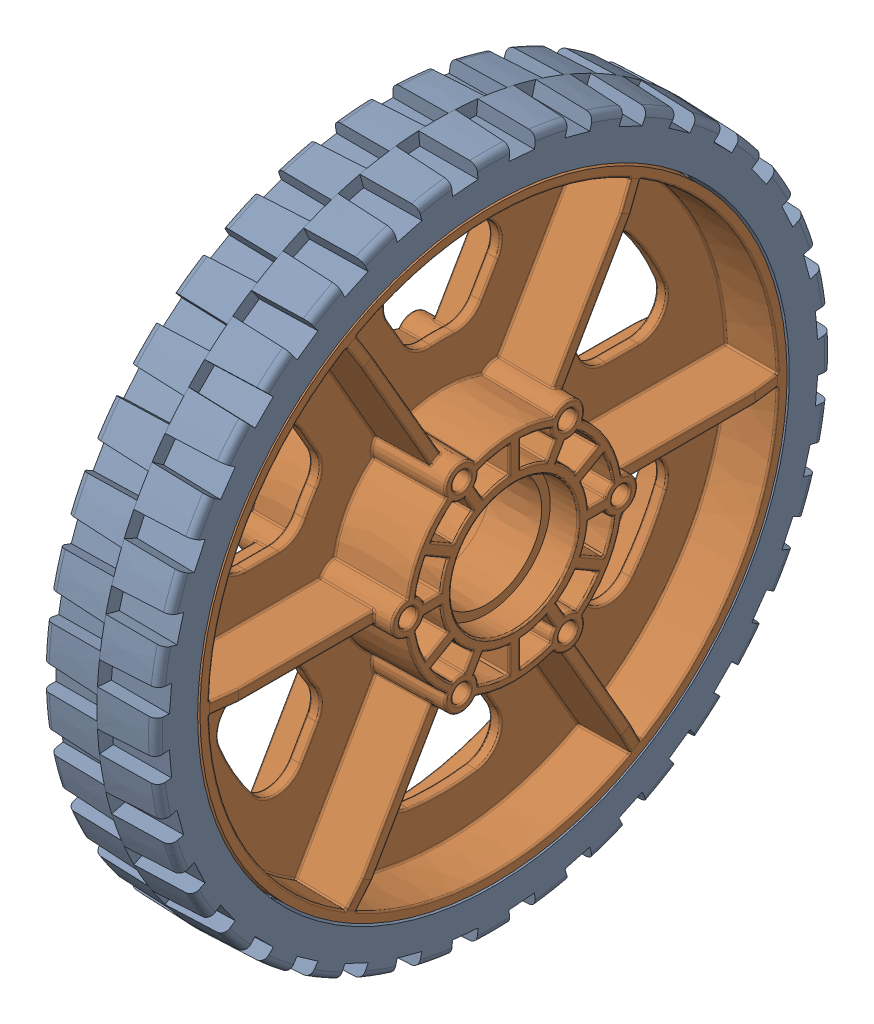
SolidWorks assembly 6 HiGrip Asm Rev II, configuration Default. Lengths in mm.
Overall size (34.93 152.4 152.4).
2 component instances, 2 part files, 0 mates.
Components (placement in the parent):
- 6 wheel tread II-1: 6 wheel tread II [Default] at (-65.3446 9.4231 21.378) x (0 0 -1) z (1 0 0) size (152.4 152.4 25.58)
- 6 wheel Rev 4-1: 6 wheel Rev 4 [Default] at (-52.6446 9.4231 21.378) size (34.93 132.08 132.08)
